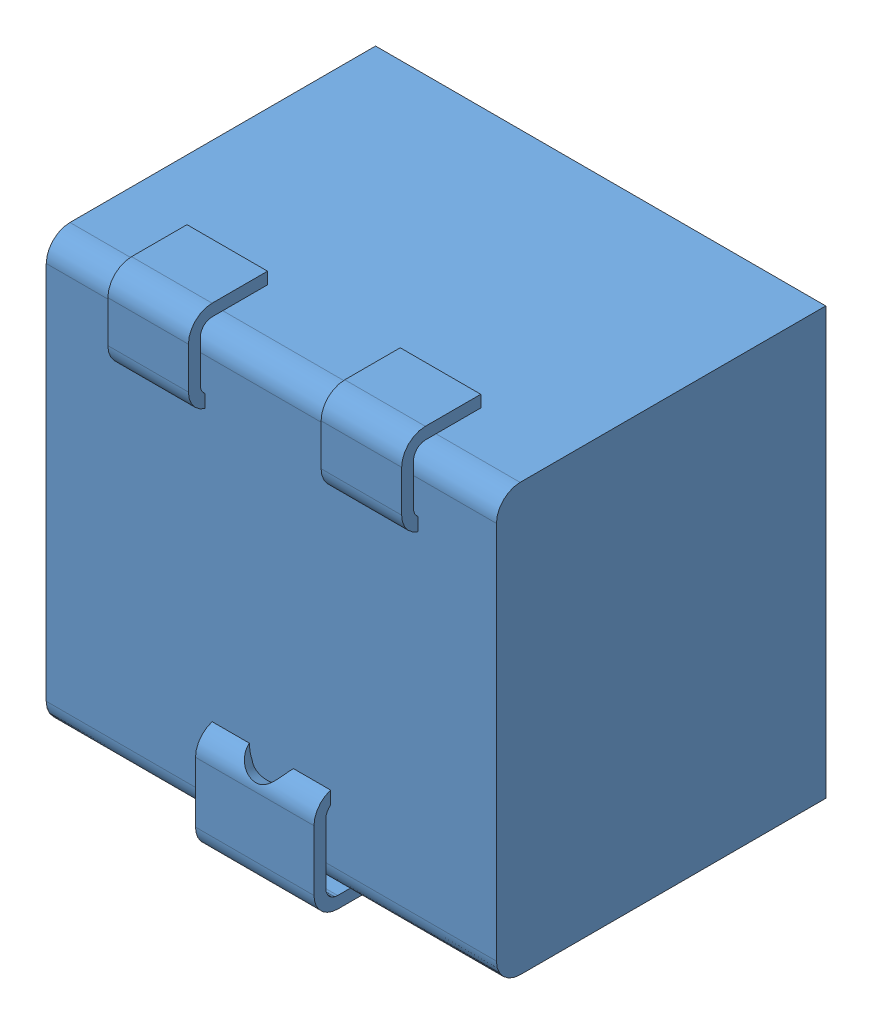
SolidWorks assembly 3224J, configuration По умолчанию. Lengths in mm.
Overall size (4.83 4.95 3.71).
7 component instances, 7 part files, 3 mates.
Components (placement in the parent):
- 3224j-1-200e-1: 3224j-1-200e [Default] at origin size (4.83 4.95 3.71)
- 3224w-1-501e_15-1: 3224w-1-501e_15 [Default] at origin size (1.54 1.11 0.01)
- 3224w-1-501e_08-3: 3224w-1-501e_08 [Default] at origin size (0.5 0.58 0.01)
- 3224w-1-501e_09-3: 3224w-1-501e_09 [Default] at origin size (0.5 0.56 0.01)
- 3224w-1-501e_10-3: 3224w-1-501e_10 [Default] at origin size (0.5 0.56 0.01)
- 3224w-1-501e_11-3: 3224w-1-501e_11 [Default] at origin size (0.5 0.54 0.01)
- J-1: J [По умолчанию] at (0.17 0.0027 -3.5306) x (-1 0 0) z (0 -1 0) size (0.23 0.01 0.55)
Mates (geometry in assembly coordinates):
- Расстояние3: distance = 0 mm: plane of J-1 through (0.6246 0.2374 -3.5306) normal (0 0 1); plane of 3224j-1-200e-1 through (-0.3048 0 -3.5306) normal (0 0 -1)
- Расстояние4: distance = 0 mm: plane of 3224w-1-501e_11-3 through (0.0754 -0.2045 -3.5338) normal (0 -1 0); plane of J-1 through (0.7223 -0.2045 -3.5366) normal (0 -1 0)
- Расстояние5: distance = 0.5 mm: plane of 3224w-1-501e_11-3 through (0.2223 0.1718 -3.5338) normal (1 0 0); plane of J-1 through (0.7223 0.1565 -3.5366) normal (1 0 0)
